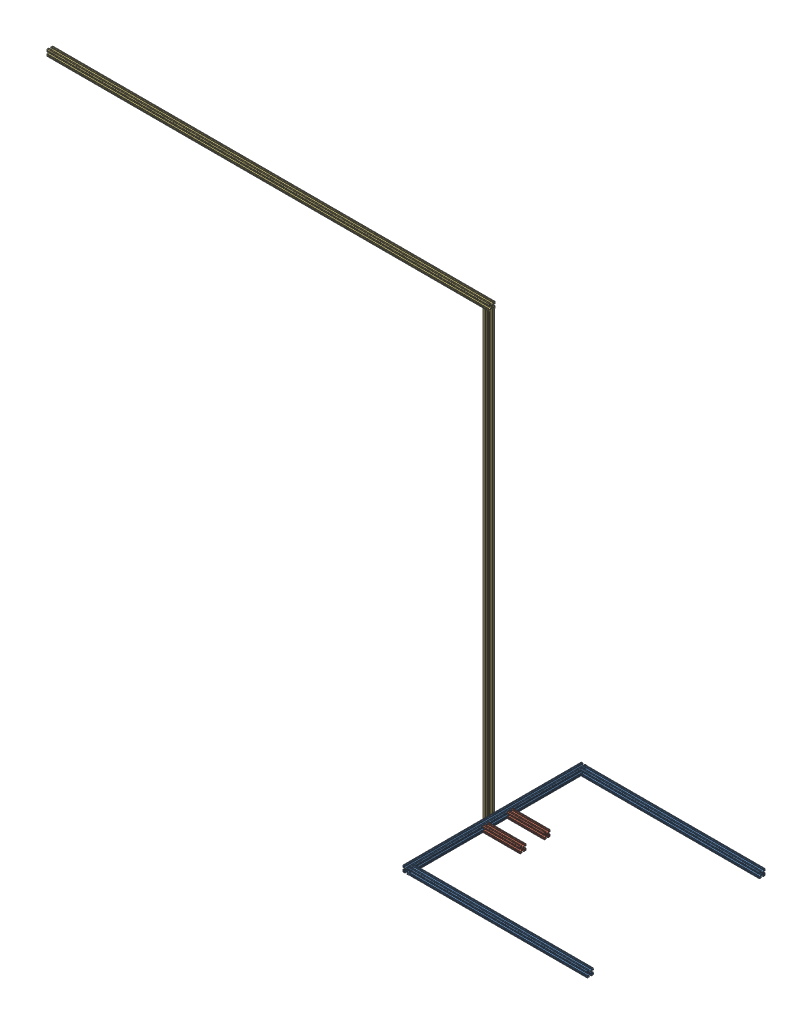
SolidWorks assembly Kite Launch Platform, configuration Default. Lengths in mm.
Overall size (2590.8 1854.2 736.6).
7 component instances, 3 part files, 18 mates.
Components (placement in the parent):
- 8020 -1inch - 2 ft 5 inchesV3-1: 8020 -1inch - 2 ft 5 inchesV3 [47065T122] at (112.0214 417.6125 628.815) size (25.4 25.4 736.6)
- 8020 -1inch - 2 ft 5 inchesV3-2: 8020 -1inch - 2 ft 5 inchesV3 [47065T122] at (493.0214 417.6125 984.415) x (0 0 1) z (-1 0 0) size (25.4 25.4 736.6)
- 8020 -1inch - 2 ft 5 inchesV3-3: 8020 -1inch - 2 ft 5 inchesV3 [47065T122] at (493.0214 417.6125 273.215) x (0 0 1) z (-1 0 0) size (25.4 25.4 736.6)
- 8020 -1inch - 0 ft 6 in-1: 8020 -1inch - 0 ft 6 in [47065T122] at (200.9214 417.6125 578.615) x (0 0 -1) z (1 0 0) size (25.4 25.4 152.4)
- 8020 -1inch - 0 ft 6 in-2: 8020 -1inch - 0 ft 6 in [47065T122] at (200.9214 417.6125 679.015) x (0 0 -1) z (1 0 0) size (25.4 25.4 152.4)
- 8020 -1inch - 6 ft 0 in-1: 8020 -1inch - 6 ft 0 in [47065T122] at (86.6214 1319.3125 628.815) x (1 0 0) z (0 1 0) size (25.4 25.4 1828.8)
- 8020 -1inch - 6 ft 0 in-2: 8020 -1inch - 6 ft 0 in [47065T122] at (-815.0786 2246.4125 628.815) x (0 0 1) z (-1 0 0) size (25.4 25.4 1828.8)
Mates (geometry in assembly coordinates):
- Coincident1: coincident aligned: plane of 8020 -1inch - 2 ft 5 inchesV3-1 through (121.5718 430.3125 997.115) normal (0 1 0); plane of 8020 -1inch - 2 ft 5 inchesV3-2 through (124.7214 430.3125 993.9655) normal (0 1 0)
- Coincident2: coincident anti-aligned: plane of 8020 -1inch - 2 ft 5 inchesV3-1 through (124.7214 423.9455 997.115) normal (1 0 0); plane of 8020 -1inch - 2 ft 5 inchesV3-2 through (124.7214 408.2026 977.9986) normal (-1 0 0)
- Coincident3: coincident aligned: plane of 8020 -1inch - 2 ft 5 inchesV3-1 through (105.605 408.2026 997.115) normal (0 0 1); plane of 8020 -1inch - 2 ft 5 inchesV3-2 through (124.7214 423.9455 997.115) normal (0 0 1)
- Coincident4: coincident anti-aligned: plane of 8020 -1inch - 2 ft 5 inchesV3-1 through (124.7214 423.9455 997.115) normal (1 0 0); plane of 8020 -1inch - 2 ft 5 inchesV3-3 through (124.7214 408.2026 266.7986) normal (-1 0 0)
- Coincident5: coincident aligned: plane of 8020 -1inch - 2 ft 5 inchesV3-1 through (121.5718 430.3125 997.115) normal (0 1 0); plane of 8020 -1inch - 2 ft 5 inchesV3-3 through (124.7214 430.3125 266.8819) normal (0 1 0)
- Coincident6: coincident aligned: plane of 8020 -1inch - 2 ft 5 inchesV3-1 through (105.605 408.2026 260.515) normal (0 0 -1); plane of 8020 -1inch - 2 ft 5 inchesV3-3 through (124.7214 427.1629 260.515) normal (0 0 -1)
- Coincident7: coincident aligned: plane of 8020 -1inch - 0 ft 6 in-1 through (277.1214 430.3125 584.9482) normal (0 1 0); plane of 8020 -1inch - 0 ft 6 in-2 through (277.1214 430.3125 669.4646) normal (0 1 0)
- Coincident8: coincident aligned: plane of 8020 -1inch - 0 ft 6 in-1 through (124.7214 408.2026 585.0315) normal (-1 0 0); plane of 8020 -1inch - 0 ft 6 in-2 through (124.7214 408.2026 685.4315) normal (-1 0 0)
- Coincident9: coincident anti-aligned: plane of 8020 -1inch - 2 ft 5 inchesV3-1 through (124.7214 423.9455 997.115) normal (1 0 0); plane of 8020 -1inch - 0 ft 6 in-2 through (124.7214 408.2026 685.4315) normal (-1 0 0)
- Distance2: distance = 75 mm anti-aligned: plane of 8020 -1inch - 0 ft 6 in-1 through (277.1214 427.1629 591.315) normal (0 0 1); plane of 8020 -1inch - 0 ft 6 in-2 through (277.1214 423.9455 666.315) normal (0 0 -1)
- Coincident12: coincident aligned: plane of 8020 -1inch - 2 ft 5 inchesV3-1 through (121.5718 430.3125 997.115) normal (0 1 0); plane of 8020 -1inch - 0 ft 6 in-1 through (277.1214 430.3125 569.0646) normal (0 1 0)
- Width1: width anti-aligned: plane of 8020 -1inch - 0 ft 6 in-2 through (277.1214 423.9455 666.315) normal (0 0 -1); plane of 8020 -1inch - 2 ft 5 inchesV3-3 through (277.1214 427.1629 591.315) normal (0 0 1); plane of 8020 -1inch - 0 ft 6 in-1 through (124.7214 423.9455 285.915) normal (0 0 1); plane of 8020 -1inch - 2 ft 5 inchesV3-2 through (124.7214 427.1629 971.715) normal (0 0 -1)
- Coincident13: coincident: plane of 8020 -1inch - 2 ft 5 inchesV3-1 through (99.3214 427.1629 997.115) normal (-1 0 0); plane of 8020 -1inch - 6 ft 0 in-1 through (99.3214 2233.7125 -293.3341) normal (1 0 0)
- Coincident15: coincident: plane of 8020 -1inch - 2 ft 5 inchesV3-1 through (102.4709 404.9125 997.115) normal (0 -1 0); plane of 8020 -1inch - 6 ft 0 in-1 through (80.205 404.9125 638.2249) normal (0 -1 0)
- Width2: width anti-aligned: plane of 8020 -1inch - 6 ft 0 in-1 through (96.1718 2233.7125 616.115) normal (0 0 -1); plane of 8020 -1inch - 0 ft 6 in-1 through (92.9545 2233.7125 641.515) normal (0 0 1); plane of 8020 -1inch - 6 ft 0 in-1 through (277.1214 427.1629 591.315) normal (0 0 1); plane of 8020 -1inch - 0 ft 6 in-2 through (277.1214 423.9455 666.315) normal (0 0 -1)
- Coincident16: coincident: plane of 8020 -1inch - 6 ft 0 in-1 through (99.3214 2233.7125 622.482) normal (1 0 0); plane of 8020 -1inch - 6 ft 0 in-2 through (99.3214 2237.0026 622.3986) normal (1 0 0)
- Coincident17: coincident: plane of 8020 -1inch - 6 ft 0 in-1 through (80.2883 2233.7125 616.115) normal (0 0 -1); plane of 8020 -1inch - 6 ft 0 in-2 through (-1729.4786 2240.0794 616.115) normal (0 0 -1)
- Coincident18: coincident anti-aligned: plane of 8020 -1inch - 6 ft 0 in-1 through (80.205 2233.7125 638.2249) normal (0 1 0); plane of 8020 -1inch - 6 ft 0 in-2 through (-1729.4786 2233.7125 619.2646) normal (0 -1 0)
